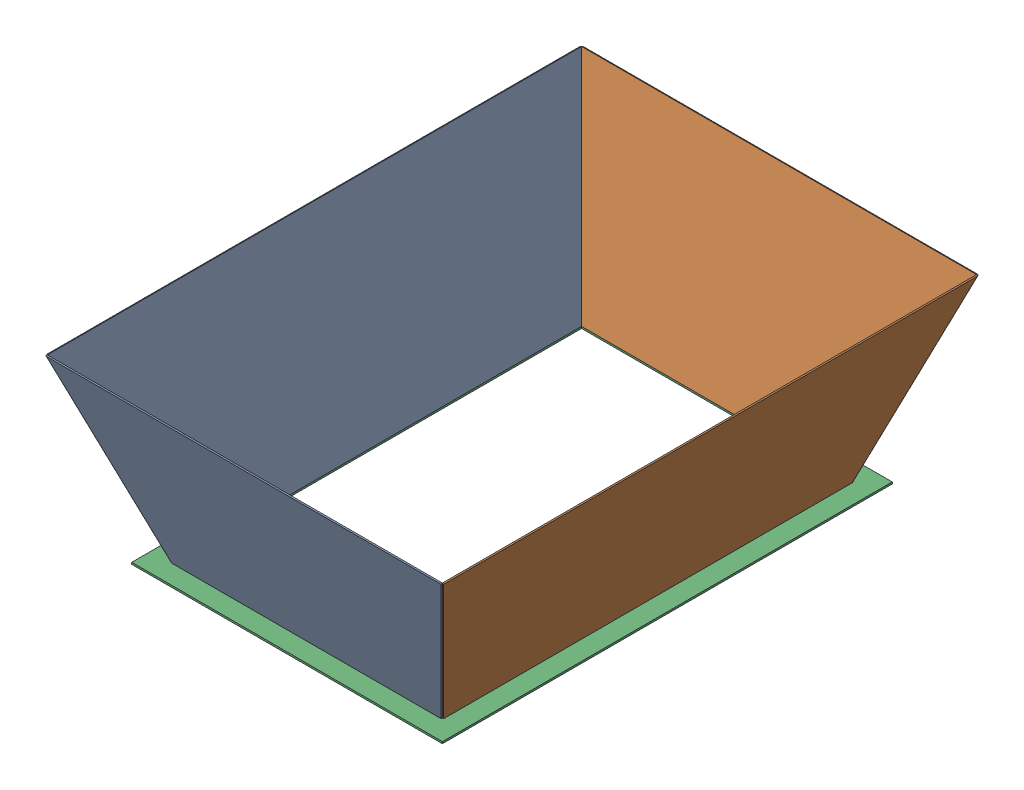
SolidWorks assembly KR.10.13, configuration Default. Lengths in mm.
Overall size (442.83 202 597.83).
3 component instances, 2 part files, 5 mates.
Components (placement in the parent):
- KR.12.21-1: KR.12.21 [Default] at (192.2234 224.7918 612.8766) size (441.42 200.67 596.42)
- KR.12.21-2: KR.12.21 [Default] at (492.2234 224.7918 157.8766) x (-1 0 0) z (0 0 -1) size (441.42 200.67 596.42)
- KR.12.22-1: KR.12.22 [Default] at (492.2234 224.7918 612.8766) x (0 0 -1) z (0 1 0) size (501 346 2)
Mates (geometry in assembly coordinates):
- Çakışık1: coincident anti-aligned: line of KR.12.21-1 through (192.2234 224.7918 157.8766) axis (-0.313678 0.896221 -0.313678); line of KR.12.21-2 through (122.2234 424.7918 87.8766) axis (0.313678 -0.896221 0.313678)
- Çakışık2: coincident anti-aligned: line of KR.12.21-1 through (562.2234 424.7918 682.8766) axis (-0.313678 -0.896221 -0.313678); line of KR.12.21-2 through (492.2234 224.7918 612.8766) axis (0.313678 0.896221 0.313678)
- Çakışık8: coincident: line of KR.12.21-1 through (192.9187 224.7918 612.8766) axis (1 0 0); plane of KR.12.22-1 through (192.7173 207.4682 612.8766) normal (0 0 -1)
- Çakışık9: coincident: line of KR.12.21-2 through (492.2234 224.7918 612.8766) axis (0 0 -1); line of KR.12.22-1 through (492.2234 224.7918 612.8766) axis (0 0 -1)
- Çakışık10: coincident: line of KR.12.21-1 through (192.2234 224.7918 157.8766) axis (0 0 1); plane of KR.12.22-1 through (192.2234 222.7918 612.8766) normal (1 0 0)
